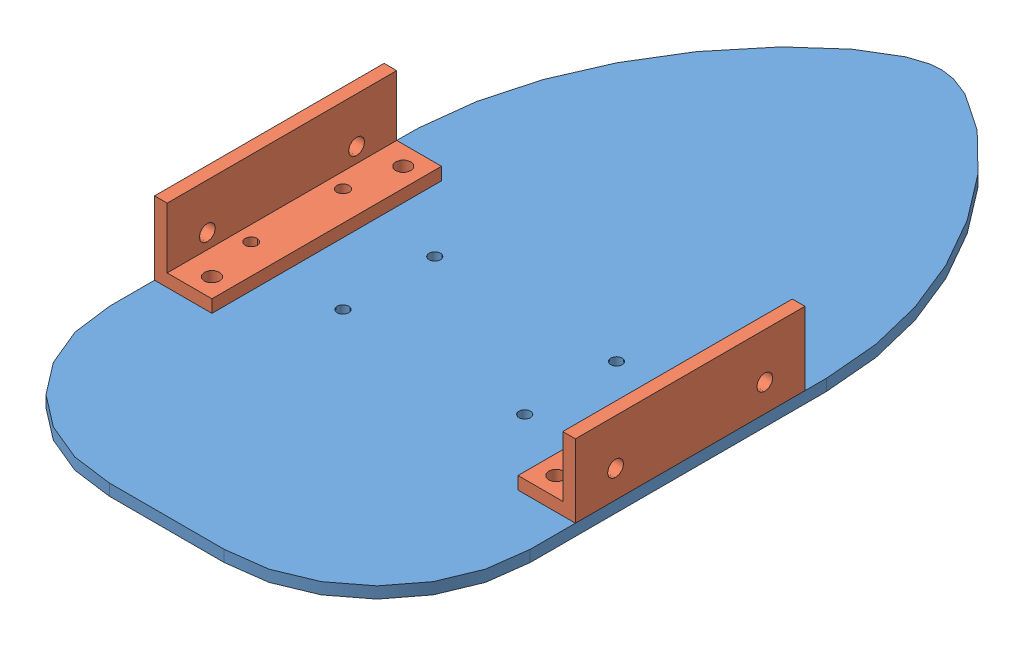
SolidWorks assembly Chassis, configuration Default. Lengths in mm.
Overall size (110 22.1 202.77).
3 component instances, 2 part files, 6 mates.
Components (placement in the parent):
- Chassis plate-1: Chassis plate [Default] at (53.1393 -0.9104 129.5074) size (110 3 202.77)
- Aluminium angle-1: Aluminium angle [Walker chassis] at (-59.8607 -8.3327 27.7074) size (15 19.1 60)
- Aluminium angle-2: Aluminium angle [Walker chassis] at (50.1393 -8.3327 27.7074) x (-1 0 0) z (0 0 -1) size (15 19.1 60)
Mates (geometry in assembly coordinates):
- Coincident6: coincident aligned: plane of Chassis plate-1 through (-59.8607 -11.3327 -94.0926) normal (-1 0 0); plane of Aluminium angle-1 through (-59.8607 -8.3327 57.7074) normal (-1 0 0)
- Coincident7: coincident anti-aligned: plane of Chassis plate-1 through (50.1393 -8.3327 -94.0926) normal (0 1 0); plane of Aluminium angle-1 through (-40.7607 -8.3327 57.7074) normal (0 -1 0)
- Distance1: distance = 30 mm: line of Aluminium angle-1 through (-59.8607 -8.3327 -2.2926) axis (1 0 0); line of Chassis plate-1 through (-83.2579 -8.3327 27.7074) axis (1 0 0)
- Coincident10: coincident aligned: plane of Aluminium angle-2 through (50.1393 -8.3327 -2.2926) normal (1 0 0); plane of Chassis plate-1 through (50.1393 -8.3327 -94.0926) normal (1 0 0)
- Coincident11: coincident anti-aligned: plane of Chassis plate-1 through (50.1393 -8.3327 -94.0926) normal (0 1 0); plane of Aluminium angle-2
- Distance2: distance = 30 mm: line of Aluminium angle-2 through (50.1393 -8.3327 -2.2926) axis (-1 0 0); line of Chassis plate-1 through (-83.2579 -8.3327 27.7074) axis (1 0 0)
